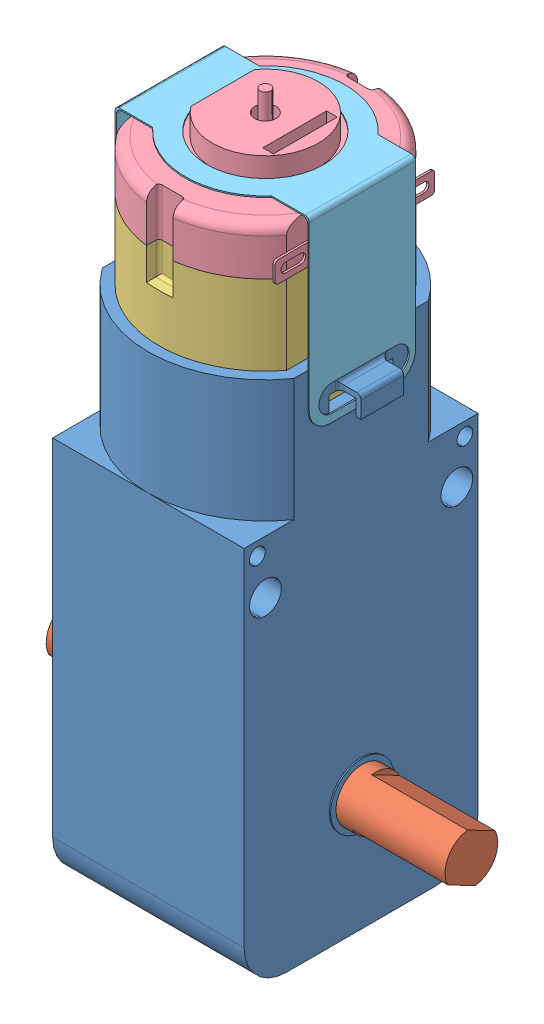
SolidWorks assembly Yellow__Gearbox__Motor, configuration Default. Lengths in mm.
Overall size (37.5 69 22).
5 component instances, 5 part files, 12 mates.
Components (placement in the parent):
- Gearbox__Base-1: Gearbox__Base [Default] at origin size (22 53 22)
- Gearbox__Shaft-1: Gearbox__Shaft [Default] at (3.875 11 0) x (0 0.887245 -0.461298) z (-1 0 0) size (4.96 4.96 37.5)
- CC__Motor__Base-1: CC__Motor__Base [Default] at (0 36.5 0) x (-1 0 0) z (0 0 -1) size (16 19 20)
- CC__Motor__Cover-1: CC__Motor__Cover [Default] at (0 55.5 0) x (-1 0 0) z (0 0 -1) size (16.77 8.5 19.96)
- CC__Motor__Attach-1: CC__Motor__Attach [Default] at (0 60.375 0) x (0 0 1) z (-1 0 0) size (15 17.75 18.25)
Mates (geometry in assembly coordinates):
- Coincident1: coordinate: point of Gearbox__Base-1
- Concentric1: concentric aligned: cylinder of Gearbox__Base-1 through (11 11 0) axis (-1 0 0) radius 2.5; circle of Gearbox__Shaft-1
- Coincident2: coincident aligned: plane of Gearbox__Base-1 through (-9.125 0 0) normal (-1 0 0); plane of Gearbox__Shaft-1 through (-9.125 11 0) normal (-1 0 0)
- Coincident3: coincident anti-aligned: plane of CC__Motor__Base-1 through (0 55.5 0) normal (0 1 0); plane of CC__Motor__Cover-1 through (0 55.5 0) normal (0 -1 0)
- Coincident4: coincident aligned: line of CC__Motor__Base-1 through (-8 55.5 -6) axis (0 0 1); line of CC__Motor__Cover-1 through (-8 55.5 -6) axis (0 0 1)
- Coincident5: coincident aligned: circle of CC__Motor__Base-1; circle of CC__Motor__Cover-1
- Coincident6: coincident anti-aligned: plane of Gearbox__Base-1 through (0 36.5 0) normal (0 1 0); plane of CC__Motor__Base-1 through (0 36.5 0) normal (0 -1 0)
- Coincident8: coincident anti-aligned: plane of Gearbox__Base-1 through (8 48 6) normal (-1 0 0); plane of CC__Motor__Base-1 through (8 55.5 -6) normal (1 0 0)
- Concentric3: concentric aligned: cylinder of Gearbox__Base-1 through (0 48 0) axis (0 -1 0) radius 10; cylinder of CC__Motor__Base-1 through (0 55.5 0) axis (0 -1 0) radius 10
- Concentric4: concentric aligned: cylinder of CC__Motor__Cover-1 through (0 62 0) axis (0 -1 0) radius 5; cylinder of CC__Motor__Attach-1 through (0 60.5 0) axis (0 -1 0) radius 5.5
- Coincident10: coincident anti-aligned: plane of Gearbox__Base-1 through (9 36.5 -11) normal (1 0 0); plane of CC__Motor__Attach-1 through (9 60.5 -7.8835) normal (-1 0 0)
- Coincident13: coincident aligned: plane of Gearbox__Base-1 through (-5 43.5 -3) normal (0 1 0); plane of CC__Motor__Attach-1 through (0 43.5 -3.1569) normal (0 1 0)
